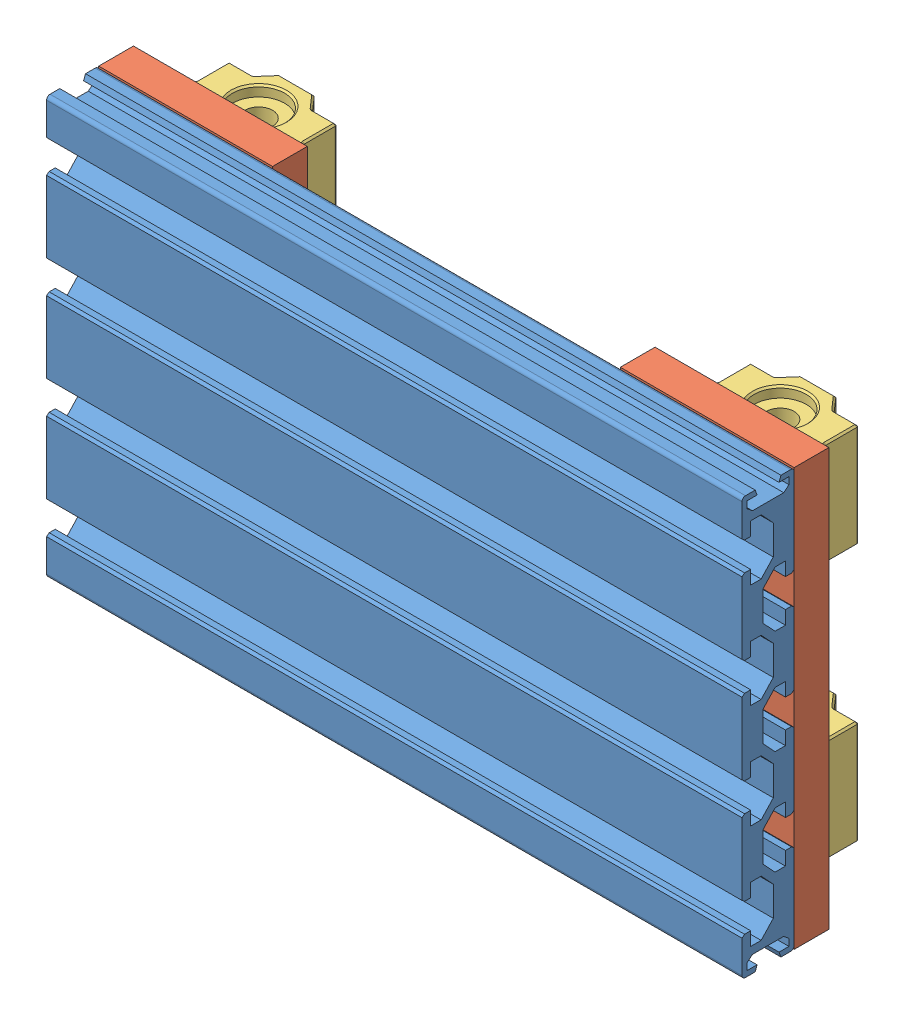
SolidWorks assembly AXIS_Y_DYNAMIC, configuration Default. Lengths in mm.
Overall size (200 120 47.8).
33 component instances, 6 part files, 71 mates.
Components (placement in the parent):
- 120x20_200_surface_profile-1: 120x20_200_surface_profile [Varsayılan] at (-100 -60 0) x (0 1 0) z (-1 0 0) size (120 15 200)
- y_axis_elevation-1: y_axis_elevation [Default] at (75 0 -10) x (0 -1 0) z (-1 0 0) size (120 10 50)
- y_axis_elevation-3: y_axis_elevation [Default] at (-75 0 -10) x (0 -1 0) z (-1 0 0) size (120 10 50)
- linear_bearing_caged-1: linear_bearing_caged [Default] at (75 37 -21) x (1 0 0) z (0 1 0) size (34 22 30)
- linear_bearing_caged-2: linear_bearing_caged [Default] at (75 -37 -21) x (1 0 0) z (0 1 0) size (34 22 30)
- linear_bearing_caged-3: linear_bearing_caged [Default] at (-75 37 -21) x (1 0 0) z (0 1 0) size (34 22 30)
- linear_bearing_caged-4: linear_bearing_caged [Default] at (-75 -37 -21) x (1 0 0) z (0 1 0) size (34 22 30)
- socket head cap screw_din-17: socket head cap screw_din [DIN 912 M4 x 16 --- 16N] at (-87 46 0) x (0 0 -1) z (1 0 0) size (20 7 7)
- socket head cap screw_din-18: socket head cap screw_din [DIN 912 M4 x 16 --- 16N] at (-63 46 0) x (0 0 -1) z (1 0 0) size (20 7 7)
- socket head cap screw_din-19: socket head cap screw_din [DIN 912 M4 x 16 --- 16N] at (-63 28 0) x (0 0 -1) z (1 0 0) size (20 7 7)
- socket head cap screw_din-20: socket head cap screw_din [DIN 912 M4 x 16 --- 16N] at (-87 28 0) x (0 0 -1) z (1 0 0) size (20 7 7)
- socket head cap screw_din-21: socket head cap screw_din [DIN 912 M4 x 16 --- 16N] at (-87 -28 0) x (0 0 -1) z (1 0 0) size (20 7 7)
- socket head cap screw_din-22: socket head cap screw_din [DIN 912 M4 x 16 --- 16N] at (-63 -28 0) x (0 0 -1) z (1 0 0) size (20 7 7)
- socket head cap screw_din-23: socket head cap screw_din [DIN 912 M4 x 16 --- 16N] at (-63 -46 0) x (0 0 -1) z (1 0 0) size (20 7 7)
- socket head cap screw_din-24: socket head cap screw_din [DIN 912 M4 x 16 --- 16N] at (-87 -46 0) x (0 0 -1) z (1 0 0) size (20 7 7)
- socket head cap screw_din-25: socket head cap screw_din [DIN 912 M4 x 16 --- 16N] at (63 46 0) x (0 0 -1) z (1 0 0) size (20 7 7)
- socket head cap screw_din-26: socket head cap screw_din [DIN 912 M4 x 16 --- 16N] at (87 46 0) x (0 0 -1) z (1 0 0) size (20 7 7)
- socket head cap screw_din-27: socket head cap screw_din [DIN 912 M4 x 16 --- 16N] at (87 28 0) x (0 0 -1) z (0.998357 0.0573 0) size (20 7 7)
- socket head cap screw_din-28: socket head cap screw_din [DIN 912 M4 x 16 --- 16N] at (63 28 0) x (0 0 -1) z (1 0 0) size (20 7 7)
- socket head cap screw_din-29: socket head cap screw_din [DIN 912 M4 x 16 --- 16N] at (63 -28 0) x (0 0 -1) z (1 0 0) size (20 7 7)
- socket head cap screw_din-30: socket head cap screw_din [DIN 912 M4 x 16 --- 16N] at (87 -28 0) x (0 0 -1) z (1 0 0) size (20 7 7)
- socket head cap screw_din-31: socket head cap screw_din [DIN 912 M4 x 16 --- 16N] at (87 -46 0) x (0 0 -1) z (1 0 0) size (20 7 7)
- socket head cap screw_din-32: socket head cap screw_din [DIN 912 M4 x 16 --- 16N] at (63 -46 0) x (0 0 -1) z (1 0 0) size (20 7 7)
- socket head cap screw_din-34: socket head cap screw_din [DIN 912 M5 x 12 --- 12N] at (75 30 -10) x (0 0 1) z (-1 0 0) size (17 8.5 8.5)
- socket head cap screw_din-35: socket head cap screw_din [DIN 912 M5 x 12 --- 12N] at (75 0 -10) x (0 0 1) z (-1 0 0) size (17 8.5 8.5)
- socket head cap screw_din-36: socket head cap screw_din [DIN 912 M5 x 12 --- 12N] at (75 -30 -10) x (0 0 1) z (-1 0 0) size (17 8.5 8.5)
- socket head cap screw_din-37: socket head cap screw_din [DIN 912 M5 x 12 --- 12N] at (-75 30 -10) x (0 0 1) z (-1 0 0) size (17 8.5 8.5)
- socket head cap screw_din-38: socket head cap screw_din [DIN 912 M5 x 12 --- 12N] at (-75 0 -10) x (0 0 1) z (-0.99859 -0.053093 0) size (17 8.5 8.5)
- socket head cap screw_din-39: socket head cap screw_din [DIN 912 M5 x 12 --- 12N] at (-75 -30 -10) x (0 0 1) z (-1 0 0) size (17 8.5 8.5)
- SK10_rod_holder-1: SK10_rod_holder [Default] at (0 -7 -20) x (1 0 0) z (0 1 0) size (42 32.8 14)
- trapezoidal_nut-1: trapezoidal_nut [Default] at (0 11 -20) x (0.999979 0 -0.006428) z (0 -1 0) size (22 22 15)
- socket head cap screw_din-42: socket head cap screw_din [DIN 912 M5 x 12 --- 12N] at (-16 0 -11) x (0 0 1) z (-1 0 0) size (17 8.5 8.5)
- socket head cap screw_din-43: socket head cap screw_din [DIN 912 M5 x 12 --- 12N] at (16 0 -11) x (0 0 1) z (-1 0 0) size (17 8.5 8.5)
Mates (geometry in assembly coordinates):
- Coincident1: coincident anti-aligned: plane of 120x20_200_surface_profile-1 through (100 35.6801 0) normal (0 0 -1); plane of y_axis_elevation-1 through (75 0 0) normal (0 0 1)
- Coincident2: coincident aligned: plane of 120x20_200_surface_profile-1 through (100 60 3.8) normal (0 1 0); plane of y_axis_elevation-1 through (50 60 0) normal (0 1 0)
- Coincident3: coincident aligned: plane of 120x20_200_surface_profile-1 through (100 -59 14) normal (1 0 0); plane of y_axis_elevation-1 through (100 -60 0) normal (1 0 0)
- Coincident4: coincident anti-aligned: plane of 120x20_200_surface_profile-1 through (100 35.6801 0) normal (0 0 -1); plane of y_axis_elevation-3 through (-75 0 0) normal (0 0 1)
- Coincident5: coincident aligned: plane of 120x20_200_surface_profile-1 through (100 60 3.8) normal (0 1 0); plane of y_axis_elevation-3 through (-100 60 0) normal (0 1 0)
- Coincident6: coincident aligned: plane of 120x20_200_surface_profile-1 through (-100 -59 14) normal (-1 0 0); plane of y_axis_elevation-3 through (-100 -60 0) normal (-1 0 0)
- Coincident13: coincident anti-aligned: plane of y_axis_elevation-3 through (-75 0 -10) normal (0 0 -1); plane of linear_bearing_caged-4 through (-92 -22 -10) normal (0 0 1)
- Coincident14: coincident anti-aligned: plane of y_axis_elevation-3 through (-75 0 -10) normal (0 0 -1); plane of linear_bearing_caged-3 through (-92 52 -10) normal (0 0 1)
- Coincident15: coincident anti-aligned: plane of y_axis_elevation-1 through (75 0 -10) normal (0 0 -1); plane of linear_bearing_caged-2 through (58 -22 -10) normal (0 0 1)
- Coincident16: coincident anti-aligned: plane of y_axis_elevation-1 through (75 0 -10) normal (0 0 -1); plane of linear_bearing_caged-1 through (58 52 -10) normal (0 0 1)
- Concentric7: concentric anti-aligned: cylinder of y_axis_elevation-3 through (-87 -46 -10) axis (0 0 1) radius 1.5; cylinder of linear_bearing_caged-4 through (-87 -46 -5.7574) axis (0 0 -1) radius 1.5
- Concentric8: concentric anti-aligned: cylinder of y_axis_elevation-3 through (-63 -28 -10) axis (0 0 1) radius 1.5; cylinder of linear_bearing_caged-4 through (-63 -28 -5.7574) axis (0 0 -1) radius 1.5
- Concentric9: concentric anti-aligned: cylinder of y_axis_elevation-3 through (-87 28 -10) axis (0 0 1) radius 1.5; cylinder of linear_bearing_caged-3 through (-87 28 -5.7574) axis (0 0 -1) radius 1.5
- Concentric10: concentric anti-aligned: cylinder of y_axis_elevation-3 through (-63 46 -10) axis (0 0 1) radius 1.5; cylinder of linear_bearing_caged-3 through (-63 46 -5.7574) axis (0 0 -1) radius 1.5
- Concentric11: concentric anti-aligned: cylinder of y_axis_elevation-1 through (63 -46 -10) axis (0 0 1) radius 1.5; cylinder of linear_bearing_caged-2 through (63 -46 -5.7574) axis (0 0 -1) radius 1.5
- Concentric12: concentric anti-aligned: cylinder of y_axis_elevation-1 through (87 -28 -10) axis (0 0 1) radius 1.5; cylinder of linear_bearing_caged-2 through (87 -28 -5.7574) axis (0 0 -1) radius 1.5
- Concentric13: concentric anti-aligned: cylinder of y_axis_elevation-1 through (63 28 -10) axis (0 0 1) radius 1.5; cylinder of linear_bearing_caged-1 through (63 28 -5.7574) axis (0 0 -1) radius 1.5
- Concentric14: concentric anti-aligned: cylinder of y_axis_elevation-1 through (87 46 -10) axis (0 0 1) radius 1.5; cylinder of linear_bearing_caged-1 through (87 46 -5.7574) axis (0 0 -1) radius 1.5
- Concentric23: concentric aligned: cylinder of y_axis_elevation-3 through (-87 46 -10) axis (0 0 1) radius 1.5; cylinder of socket head cap screw_din-17 through (-87 46 31.75) axis (0 0 1) radius 3.5
- Coincident26: coincident anti-aligned: plane of y_axis_elevation-3 through (-87 46 -4) normal (0 0 1); plane of socket head cap screw_din-17 through (-87 49.5 -4) normal (0 0 -1)
- Concentric24: concentric aligned: cylinder of y_axis_elevation-3 through (-63 46 -10) axis (0 0 1) radius 1.5; cylinder of socket head cap screw_din-18 through (-63 46 31.75) axis (0 0 1) radius 3.5
- Coincident27: coincident anti-aligned: plane of y_axis_elevation-3 through (-63 46 -4) normal (0 0 1); plane of socket head cap screw_din-18 through (-63 49.5 -4) normal (0 0 -1)
- Concentric25: concentric aligned: cylinder of y_axis_elevation-3 through (-63 28 -10) axis (0 0 1) radius 1.5; cylinder of socket head cap screw_din-19 through (-63 28 31.75) axis (0 0 1) radius 3.5
- Coincident28: coincident anti-aligned: plane of y_axis_elevation-3 through (-63 28 -4) normal (0 0 1); plane of socket head cap screw_din-19 through (-63 31.5 -4) normal (0 0 -1)
- Concentric26: concentric aligned: cylinder of y_axis_elevation-3 through (-87 28 -10) axis (0 0 1) radius 1.5; cylinder of socket head cap screw_din-20 through (-87 28 31.75) axis (0 0 1) radius 3.5
- Coincident29: coincident anti-aligned: plane of y_axis_elevation-3 through (-87 28 -4) normal (0 0 1); plane of socket head cap screw_din-20 through (-87 31.5 -4) normal (0 0 -1)
- Concentric27: concentric aligned: cylinder of y_axis_elevation-3 through (-87 -28 -10) axis (0 0 1) radius 1.5; cylinder of socket head cap screw_din-21 through (-87 -28 31.75) axis (0 0 1) radius 3.5
- Coincident30: coincident anti-aligned: plane of y_axis_elevation-3 through (-87 -28 -4) normal (0 0 1); plane of socket head cap screw_din-21 through (-87 -24.5 -4) normal (0 0 -1)
- Concentric28: concentric aligned: cylinder of y_axis_elevation-3 through (-63 -28 -4) axis (0 0 1) radius 3.5; cylinder of socket head cap screw_din-22 through (-63 -28 31.75) axis (0 0 1) radius 3.5
- Coincident31: coincident anti-aligned: plane of y_axis_elevation-3 through (-63 -28 -4) normal (0 0 1); plane of socket head cap screw_din-22 through (-63 -24.5 -4) normal (0 0 -1)
- Concentric29: concentric aligned: cylinder of y_axis_elevation-3 through (-63 -46 -10) axis (0 0 1) radius 1.5; cylinder of socket head cap screw_din-23 through (-63 -46 31.75) axis (0 0 1) radius 3.5
- Coincident32: coincident anti-aligned: plane of y_axis_elevation-3 through (-63 -46 -4) normal (0 0 1); plane of socket head cap screw_din-23 through (-63 -42.5 -4) normal (0 0 -1)
- Concentric30: concentric aligned: cylinder of y_axis_elevation-3 through (-87 -46 -10) axis (0 0 1) radius 1.5; cylinder of socket head cap screw_din-24 through (-87 -46 31.75) axis (0 0 1) radius 3.5
- Coincident33: coincident anti-aligned: plane of y_axis_elevation-3 through (-87 -46 -4) normal (0 0 1); plane of socket head cap screw_din-24 through (-87 -42.5 -4) normal (0 0 -1)
- Concentric31: concentric aligned: cylinder of y_axis_elevation-1 through (63 46 -10) axis (0 0 1) radius 1.5; cylinder of socket head cap screw_din-25 through (63 46 31.75) axis (0 0 1) radius 3.5
- Coincident34: coincident anti-aligned: plane of y_axis_elevation-1 through (63 46 -4) normal (0 0 1); plane of socket head cap screw_din-25 through (63 49.5 -4) normal (0 0 -1)
- Concentric32: concentric aligned: cylinder of y_axis_elevation-1 through (87 46 -4) axis (0 0 1) radius 3.5; cylinder of socket head cap screw_din-26 through (87 46 31.75) axis (0 0 1) radius 3.5
- Coincident35: coincident anti-aligned: plane of y_axis_elevation-1 through (87 46 -4) normal (0 0 1); plane of socket head cap screw_din-26 through (87 49.5 -4) normal (0 0 -1)
- Concentric33: concentric aligned: cylinder of y_axis_elevation-1 through (87 28 -4) axis (0 0 1) radius 3.5; cylinder of socket head cap screw_din-27 through (87 28 31.75) axis (0 0 1) radius 3.5
- Concentric34: concentric aligned: cylinder of y_axis_elevation-1 through (63 28 -4) axis (0 0 1) radius 3.5; cylinder of socket head cap screw_din-28 through (63 28 31.75) axis (0 0 1) radius 3.5
- Coincident37: coincident anti-aligned: plane of y_axis_elevation-1 through (63 28 -4) normal (0 0 1); plane of socket head cap screw_din-28 through (63 31.5 -4) normal (0 0 -1)
- Concentric35: concentric aligned: cylinder of y_axis_elevation-1 through (63 -28 -4) axis (0 0 1) radius 3.5; cylinder of socket head cap screw_din-29 through (63 -28 31.75) axis (0 0 1) radius 3.5
- Coincident38: coincident anti-aligned: plane of y_axis_elevation-1 through (63 -28 -4) normal (0 0 1); plane of socket head cap screw_din-29 through (63 -24.5 -4) normal (0 0 -1)
- Concentric36: concentric aligned: cylinder of y_axis_elevation-1 through (87 -28 -10) axis (0 0 1) radius 1.5; cylinder of socket head cap screw_din-30 through (87 -28 31.75) axis (0 0 1) radius 3.5
- Coincident39: coincident anti-aligned: plane of y_axis_elevation-1 through (87 -28 -4) normal (0 0 1); plane of socket head cap screw_din-30 through (87 -24.5 -4) normal (0 0 -1)
- Concentric37: concentric aligned: cylinder of y_axis_elevation-1 through (87 -46 -10) axis (0 0 1) radius 1.5; cylinder of socket head cap screw_din-31 through (87 -46 31.75) axis (0 0 1) radius 3.5
- Coincident40: coincident anti-aligned: plane of y_axis_elevation-1 through (87 -46 -4) normal (0 0 1); plane of socket head cap screw_din-31 through (87 -42.5 -4) normal (0 0 -1)
- Concentric38: concentric aligned: cylinder of y_axis_elevation-1 through (63 -46 -10) axis (0 0 1) radius 1.5; cylinder of socket head cap screw_din-32 through (63 -46 31.75) axis (0 0 1) radius 3.5
- Coincident41: coincident anti-aligned: plane of y_axis_elevation-1 through (63 -46 -4) normal (0 0 1); plane of socket head cap screw_din-32 through (63 -42.5 -4) normal (0 0 -1)
- Coincident42: coincident anti-aligned: plane of y_axis_elevation-1 through (87 28 -4) normal (0 0 1); plane of socket head cap screw_din-27 through (86.7995 31.4942 -4) normal (0 0 -1)
- Concentric39: concentric aligned: cylinder of y_axis_elevation-1 through (75 30 0) axis (0 0 -1) radius 2.5; cylinder of socket head cap screw_din-34 through (75 30 -41.75) axis (0 0 -1) radius 4.25
- Coincident43: coincident anti-aligned: plane of y_axis_elevation-1 through (75 30 -5) normal (0 0 -1); plane of socket head cap screw_din-34 through (75 34.25 -5) normal (0 0 1)
- Concentric40: concentric aligned: cylinder of y_axis_elevation-1 through (75 0 -5) axis (0 0 -1) radius 4.25; cylinder of socket head cap screw_din-35 through (75 0 -41.75) axis (0 0 -1) radius 4.25
- Coincident44: coincident anti-aligned: plane of y_axis_elevation-1 through (75 0 -5) normal (0 0 -1); plane of socket head cap screw_din-35 through (75 4.25 -5) normal (0 0 1)
- Concentric41: concentric aligned: cylinder of y_axis_elevation-1 through (75 -30 -5) axis (0 0 -1) radius 4.25; cylinder of socket head cap screw_din-36 through (75 -30 -41.75) axis (0 0 -1) radius 4.25
- Coincident45: coincident anti-aligned: plane of y_axis_elevation-1 through (75 -30 -5) normal (0 0 -1); plane of socket head cap screw_din-36 through (75 -25.75 -5) normal (0 0 1)
- Concentric42: concentric aligned: cylinder of y_axis_elevation-3 through (-75 30 -5) axis (0 0 -1) radius 4.25; cylinder of socket head cap screw_din-37 through (-75 30 -41.75) axis (0 0 -1) radius 4.25
- Coincident46: coincident anti-aligned: plane of y_axis_elevation-3 through (-75 30 -5) normal (0 0 -1); plane of socket head cap screw_din-37 through (-75 34.25 -5) normal (0 0 1)
- Concentric43: concentric aligned: cylinder of y_axis_elevation-3 through (-75 0 0) axis (0 0 -1) radius 2.5; cylinder of socket head cap screw_din-38 through (-75 0 -41.75) axis (0 0 -1) radius 4.25
- Coincident47: coincident anti-aligned: plane of y_axis_elevation-3 through (-75 0 -5) normal (0 0 -1); plane of socket head cap screw_din-38 through (-75.2256 4.244 -5) normal (0 0 1)
- Concentric44: concentric aligned: cylinder of y_axis_elevation-3 through (-75 -30 -5) axis (0 0 -1) radius 4.25; cylinder of socket head cap screw_din-39 through (-75 -30 -41.75) axis (0 0 -1) radius 4.25
- Coincident48: coincident anti-aligned: plane of y_axis_elevation-3 through (-75 -30 -5) normal (0 0 -1); plane of socket head cap screw_din-39 through (-75 -25.75 -5) normal (0 0 1)
- Coincident49: coincident anti-aligned: plane of 120x20_200_surface_profile-1 through (100 25.3 0) normal (0 0 -1); plane of SK10_rod_holder-1 through (-21 7 0) normal (0 0 1)
- Width1: width anti-aligned: plane of SK10_rod_holder-1 through (0 7 -20) normal (0 1 0); plane of SK10_rod_holder-1 through (0 -7 -20) normal (0 -1 0); plane of 120x20_200_surface_profile-1 through (100 -55.25 3) normal (0 -1 0); plane of 120x20_200_surface_profile-1 through (100 55.25 12) normal (0 1 0)
- Width2: width anti-aligned: plane of SK10_rod_holder-1 through (-9 7 -32.8) normal (-1 0 0); plane of SK10_rod_holder-1 through (9 7 -32.8) normal (1 0 0); plane of 120x20_200_surface_profile-1 through (-100 -59 14) normal (-1 0 0); plane of 120x20_200_surface_profile-1 through (100 -59 14) normal (1 0 0)
- Coincident51: coincident anti-aligned: plane of SK10_rod_holder-1 through (0 7 -20) normal (0 1 0); plane of trapezoidal_nut-1 through (0 7 -20) normal (0 -1 0)
- Concentric45: concentric anti-aligned: cylinder of SK10_rod_holder-1 through (0 7 -20) axis (0 -1 0) radius 5; cylinder of trapezoidal_nut-1 through (0 -4 -20) axis (0 1 0) radius 5.15
- Concentric47: concentric aligned: cylinder of SK10_rod_holder-1 through (-16 0 0) axis (0 0 -1) radius 2.75; cylinder of socket head cap screw_din-42 through (-16 0 -42.75) axis (0 0 -1) radius 4.25
- Coincident53: coincident anti-aligned: plane of SK10_rod_holder-1 through (-9 7 -6) normal (0 0 -1); plane of socket head cap screw_din-42 through (-16 4.25 -6) normal (0 0 1)
- Concentric48: concentric aligned: cylinder of SK10_rod_holder-1 through (16 0 0) axis (0 0 -1) radius 2.75; cylinder of socket head cap screw_din-43 through (16 0 -42.75) axis (0 0 -1) radius 4.25
- Coincident54: coincident anti-aligned: plane of SK10_rod_holder-1 through (9 7 -6) normal (0 0 -1); plane of socket head cap screw_din-43 through (16 4.25 -6) normal (0 0 1)
